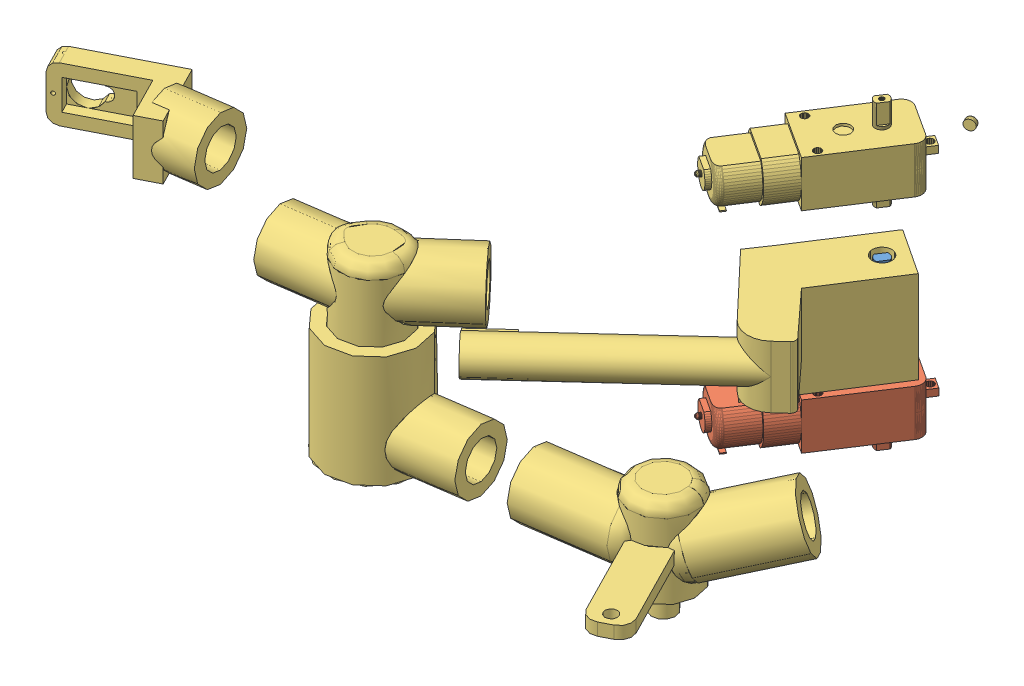
SolidWorks assembly Assem1, configuration Default. Lengths in mm.
Overall size (182.07 69.56 202.03).
3 component instances, 3 part files, 6 mates.
Components (placement in the parent):
- Angled Motor shaft extension-1: Angled Motor shaft extension [Default] at (9.6313 18.5653 89.368) x (-0.837169 0 -0.546944) z (-0.546944 0 0.837169) size (20.59 45 25.1)
- Angled Motor-1: Angled Motor [Default] at (9.6313 26.3653 89.368) x (0.837169 0 0.546944) z (0.546944 0 -0.837169) size (22.4 36.6 70.6)
- Bogie - Motor mount - RIGHT VF-1: Bogie - Motor mount - RIGHT VF [Default] at (23.6956 57.7993 146.5469) x (-0.890825 0 0.454346) z (0 1 0) size (251.14 245.94 117.56)
Mates (geometry in assembly coordinates):
- Concentric1: concentric anti-aligned: circle of Angled Motor-1; cylinder of Bogie - Motor mount - RIGHT VF-1 through (9.6313 74.7553 89.368) axis (0 -1 0) radius 3.9367
- Coincident1: coincident anti-aligned: plane of Angled Motor-1 through (9.6313 37.6653 89.368) normal (0 1 0); plane of Bogie - Motor mount - RIGHT VF-1 through (23.6956 37.6653 146.5469) normal (0 -1 0)
- Parallel1: parallel anti-aligned: line of Angled Motor-1 through (-13.8562 35.6653 104.8412) axis (0.546944 0 -0.837169); line of Bogie - Motor mount - RIGHT VF-1 through (4.6969 37.6653 76.6382) axis (-0.546944 0 0.837169)
- Coincident6: coincident anti-aligned: plane of Angled Motor shaft extension-1 through (33.1268 36.8653 53.4051) normal (0 -1 0); plane of Angled Motor-1 through (9.6313 36.8653 89.368) normal (0 1 0)
- Coincident7: coincident anti-aligned: plane of Angled Motor shaft extension-1 through (34.6755 18.5653 54.4169) normal (-0.837169 0 -0.546944); plane of Angled Motor-1 through (11.18 26.3653 90.3799) normal (0.837169 0 0.546944)
- Concentric4: concentric aligned: circle of Angled Motor shaft extension-1; circle of Angled Motor-1
